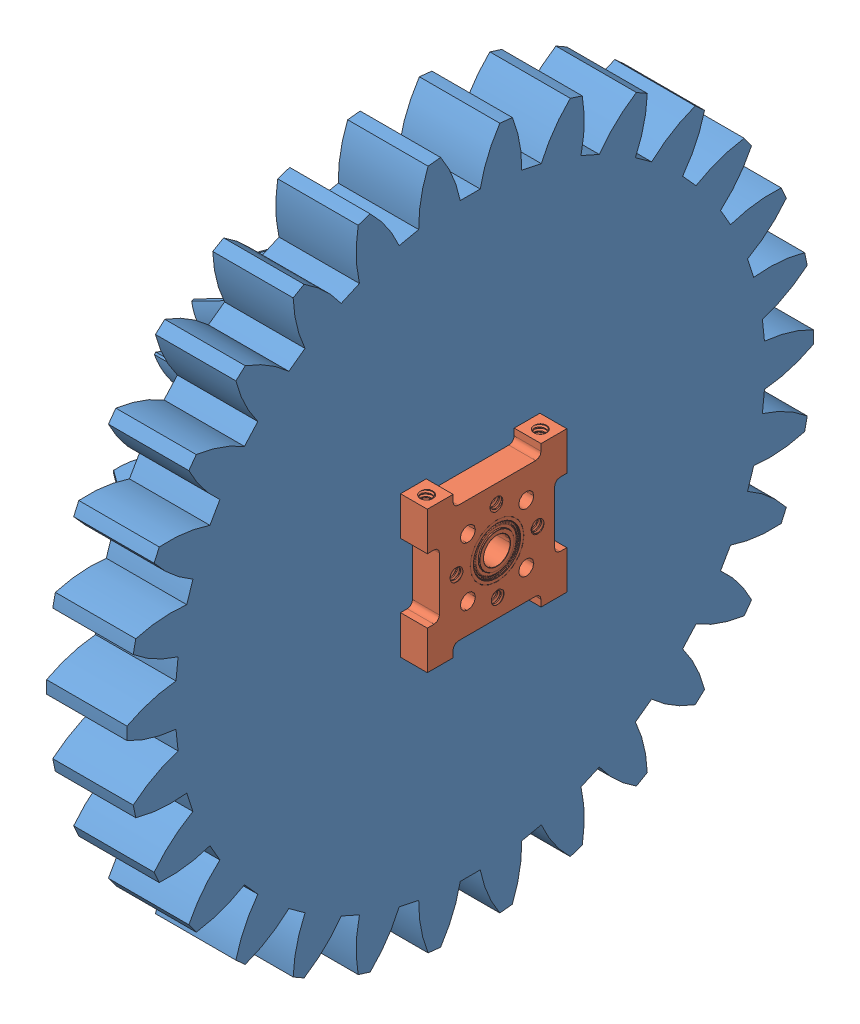
SolidWorks assembly ARMUS-REV2-300, configuration Default. Lengths in mm.
Overall size (57.21 161.95 162.56).
3 component instances, 2 part files, 7 mates.
Components (placement in the parent):
- ARMUS-REV2-301-1: ARMUS-REV2-301 [Default] at origin size (50.86 161.95 162.56)
- Bore Side Tapped Pillow Block 1.25-1: Bore Side Tapped Pillow Block 1.25 [Default] at (-39.4159 7.6184 -28.3917) x (0 -1 0) z (0 0 1) size (33.54 6.35 33.02)
- Bore Side Tapped Pillow Block 1.25-2: Bore Side Tapped Pillow Block 1.25 [Default] at (4.8346 7.6184 -28.3917) x (0 -1 0) z (0 0 1) size (33.54 6.35 33.02)
Mates (geometry in assembly coordinates):
- Coincident1: coordinate: point of ARMUS-REV2-100-1
- Concentric1: concentric anti-aligned: cylinder of ARMUS-REV2-100-1 through (-86.1279 0 0) axis (1 0 0) radius 6.35; cylinder of Bore Side Tapped Pillow Block 1.25-1 through (-18.8631 0 0) axis (-1 0 0) radius 3.175
- Parallel1: parallel aligned: plane of ARMUS-REV2-100-1 through (0 0 0) normal (0 1 0); plane of Bore Side Tapped Pillow Block 1.25-1 through (-18.8504 13.9065 -10.414) normal (0 1 0)
- Coincident3: coincident anti-aligned: plane of ARMUS-REV2-100-1 through (-18.8504 0 0) normal (-1 0 0); plane of Bore Side Tapped Pillow Block 1.25-1 through (-18.8504 0 0) normal (1 0 0)
- Concentric2: concentric anti-aligned: cylinder of ARMUS-REV2-100-1 through (-86.1279 0 0) axis (1 0 0) radius 6.35; cylinder of Bore Side Tapped Pillow Block 1.25-2 through (25.3873 0 0) axis (-1 0 0) radius 3.175
- Parallel2: parallel aligned: plane of Bore Side Tapped Pillow Block 1.25-1 through (-18.8504 13.9065 -10.414) normal (0 1 0); plane of Bore Side Tapped Pillow Block 1.25-2 through (25.4 13.9065 -10.414) normal (0 1 0)
- Coincident4: coincident anti-aligned: plane of ARMUS-REV2-100-1 through (19.05 0 0) normal (1 0 0); plane of Bore Side Tapped Pillow Block 1.25-2 through (19.05 0 0) normal (-1 0 0)
